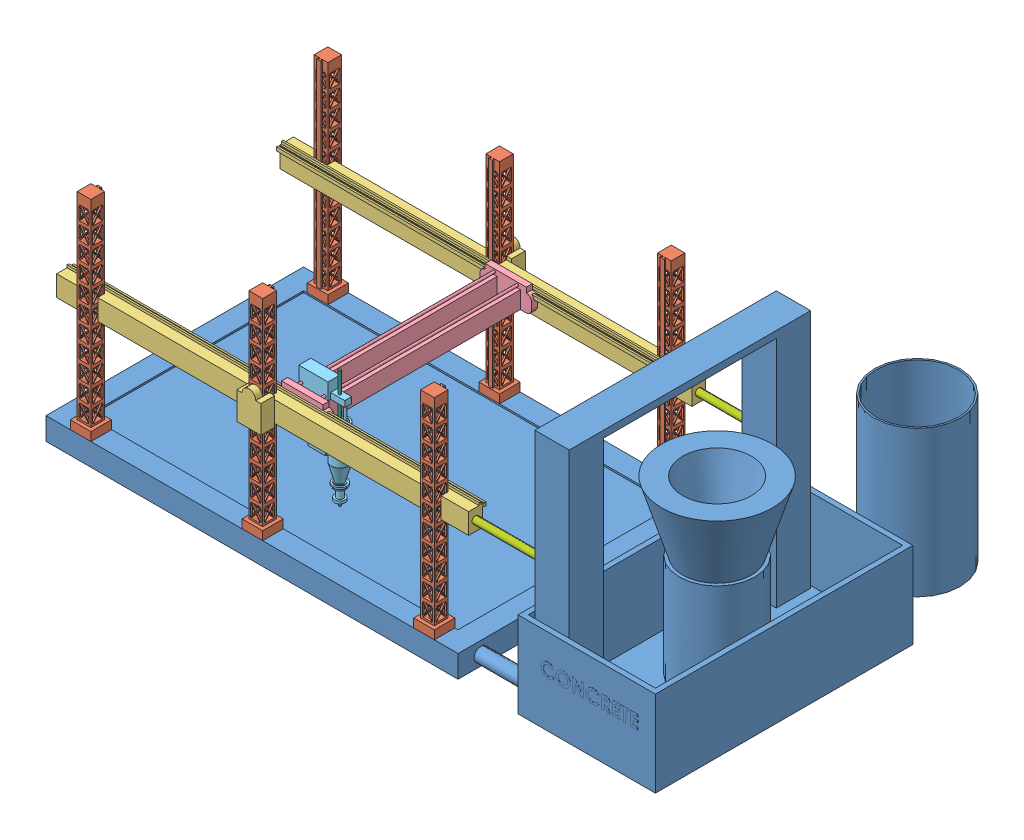
SolidWorks assembly 3-D conc printing, configuration Default. Lengths in mm.
Overall size (9014.85 3683 5637.34).
14 component instances, 7 part files, 41 mates.
Components (placement in the parent):
- base-1: base [Default] at (2368.0723 3073.6153 4815.6142) x (1 0 0) z (0 -1 0) size (9014.85 5587.54 3683)
- coloumn-3: coloumn [Default] at (4912.0124 4600.1553 6466.6142) x (0 -1 0) z (0 0 -1) size (3050.54 304.8 304.8)
- coloumn-4: coloumn [Default] at (2371.8654 4600.1553 3164.6142) x (0 -1 0) z (0 0 1) size (3050.54 304.8 304.8)
- coloumn-5: coloumn [Default] at (4911.8654 4600.1553 3164.6142) x (0 -1 0) z (0 0 1) size (3050.54 304.8 304.8)
- coloumn-6: coloumn [Default] at (-168.1346 4600.1553 3164.6142) x (0 -1 0) z (0 0 1) size (3050.54 304.8 304.8)
- coloumn-2: coloumn [Default] at (-167.9876 4600.1553 6466.6142) x (0 -1 0) z (0 0 -1) size (3050.54 304.8 304.8)
- coloumn-7: coloumn [Default] at (2372.0124 4600.1553 6466.6142) x (0 -1 0) z (0 0 -1) size (3050.54 304.8 304.8)
- beam-1: beam [Default] at (2372.0124 4664.3962 6568.2142) size (6096 508 457.2)
- beam-3: beam [Default] at (2371.8654 4664.3962 3063.0142) x (-1 0 0) z (0 0 -1) size (6096 508 457.2)
- tool post-1: tool post [Default] at (2755.9961 4829.4676 4815.6142) x (0 0 -1) z (0 1 0) size (3098.8 762 330.2)
- nozzle-3: nozzle [Default] at (3059.3592 4054.7676 6112.1341) x (-1 0 0) z (0 -1 0) size (646.26 254 1587.5)
- helix-1: helix [Default] at (3059.3592 4032.5534 6112.1341) x (0.953783 0 -0.300495) z (0 1 0) size (173.07 173.07 1193.48)
- pipe-2: pipe [Default] at (5420.0124 4664.4201 6468.4264) x (0 0 -1) z (1 0 0) size (101.6 101.6 1018.54)
- pipe-3: pipe [Default] at (5419.8654 4650.852 3166.0298) x (0 0 -1) z (1 0 0) size (101.6 101.6 1018.54)
Mates (geometry in assembly coordinates):
- Coincident4: coincident anti-aligned: plane of base-1 through (2368.0723 3073.6153 4815.6142) normal (0 1 0); plane of coloumn-2 through (-167.9876 3073.6153 6466.6142) normal (0 -1 0)
- Coincident7: coincident anti-aligned: plane of base-1 through (2368.0723 3073.6153 4815.6142) normal (0 1 0); plane of coloumn-7 through (2372.0124 3073.6153 6466.6142) normal (0 -1 0)
- Coincident10: coincident anti-aligned: plane of base-1 through (2368.0723 3073.6153 4815.6142) normal (0 1 0); plane of coloumn-3 through (4912.0124 3073.6153 6466.6142) normal (0 -1 0)
- Coincident12: coincident anti-aligned: plane of base-1 through (2368.0723 3073.6153 4815.6142) normal (0 1 0); plane of coloumn-4 through (2371.8654 3073.6153 3164.6142) normal (0 -1 0)
- Coincident13: coincident aligned: plane of base-1 through (-679.9277 2743.4153 2910.6142) normal (0 0 -1); plane of coloumn-4 through (2219.4654 3073.6153 2910.6142) normal (0 0 -1)
- Coincident14: coincident anti-aligned: plane of base-1 through (2368.0723 3073.6153 4815.6142) normal (0 1 0); plane of coloumn-6 through (-168.1346 3073.6153 3164.6142) normal (0 -1 0)
- Coincident15: coincident aligned: plane of base-1 through (-679.9277 2743.4153 2910.6142) normal (0 0 -1); plane of coloumn-6 through (-320.5346 3073.6153 2910.6142) normal (0 0 -1)
- Coincident16: coincident anti-aligned: plane of base-1 through (2368.0723 3073.6153 4815.6142) normal (0 1 0); plane of coloumn-5 through (4911.8654 3073.6153 3164.6142) normal (0 -1 0)
- Coincident17: coincident aligned: plane of base-1 through (-679.9277 2743.4153 2910.6142) normal (0 0 -1); plane of coloumn-5 through (4759.4654 3073.6153 2910.6142) normal (0 0 -1)
- Coincident19: coincident aligned: plane of base-1 through (-679.9277 2743.4153 6720.6142) normal (0 0 1); plane of coloumn-3 through (5064.4124 3073.6153 6720.6142) normal (0 0 1)
- Coincident20: coincident aligned: plane of base-1 through (-679.9277 2743.4153 6720.6142) normal (0 0 1); plane of coloumn-7 through (2524.4124 3073.6153 6720.6142) normal (0 0 1)
- Coincident21: coincident aligned: plane of base-1 through (-679.9277 2743.4153 6720.6142) normal (0 0 1); plane of coloumn-2 through (-15.5876 3073.6153 6720.6142) normal (0 0 1)
- Coincident24: coincident anti-aligned: plane of coloumn-2 through (-136.2376 3129.6201 6434.8642) normal (0 0 -1); plane of beam-1 through (-199.7376 5782.1132 6434.8642) normal (0 0 1)
- Coincident25: coincident anti-aligned: plane of coloumn-2 through (-66.3876 6124.1553 6669.8142) normal (1 0 0); plane of beam-1 through (-66.3876 5782.1132 6568.2142) normal (-1 0 0)
- Coincident26: coincident anti-aligned: plane of coloumn-7 through (2403.7624 3129.6201 6434.8642) normal (0 0 -1); plane of beam-1 through (2340.2624 5782.1132 6434.8642) normal (0 0 1)
- Coincident27: coincident anti-aligned: plane of coloumn-7 through (2270.4124 6124.1553 6669.8142) normal (-1 0 0); plane of beam-1 through (2270.4124 5782.1132 6568.2142) normal (1 0 0)
- Coincident28: coincident anti-aligned: plane of coloumn-3 through (4943.7624 3129.6201 6434.8642) normal (0 0 -1); plane of beam-1 through (4880.2624 5782.1132 6434.8642) normal (0 0 1)
- Coincident29: coincident anti-aligned: plane of coloumn-3 through (4810.4124 6124.1553 6669.8142) normal (-1 0 0); plane of beam-1 through (4810.4124 5782.1132 6568.2142) normal (1 0 0)
- Distance1: distance = 351.6599 mm aligned: plane of coloumn-3 through (5064.4124 3073.6153 6415.8142) normal (1 0 0); plane of base-1 through (5416.0723 2743.4153 2910.6142) normal (1 0 0)
- LimitDistance2: limit distance = 1307.3591 mm aligned: plane of coloumn-7 through (2270.4124 6124.1553 6669.8142) normal (0 1 0); plane of beam-1 through (-675.9876 4816.7962 6365.0142) normal (0 1 0)
- Coincident43: coincident anti-aligned: plane of coloumn-4 through (2340.1154 3129.6201 3196.3642) normal (0 0 1); plane of beam-3 through (2403.6154 5782.1132 3196.3642) normal (0 0 -1)
- Coincident44: coincident anti-aligned: plane of coloumn-4 through (2270.2654 6124.1553 2961.4142) normal (-1 0 0); plane of beam-3 through (2270.2654 5782.1132 3063.0142) normal (1 0 0)
- Coincident45: coincident anti-aligned: plane of coloumn-6 through (-199.8846 3129.6201 3196.3642) normal (0 0 1); plane of beam-3 through (-136.3846 5782.1132 3196.3642) normal (0 0 -1)
- Coincident47: coincident anti-aligned: plane of coloumn-5 through (4880.1154 3129.6201 3196.3642) normal (0 0 1); plane of beam-3 through (4943.6154 5782.1132 3196.3642) normal (0 0 -1)
- Coincident48: coincident anti-aligned: plane of coloumn-5 through (5013.4654 6124.1553 2961.4142) normal (1 0 0); plane of beam-3 through (5013.4654 5782.1132 3063.0142) normal (-1 0 0)
- LimitDistance4: limit distance = 1307.3591 mm aligned: plane of beam-3 through (5419.8654 4816.7962 3266.2142) normal (0 1 0); plane of coloumn-4 through (2473.4654 6124.1553 2961.4142) normal (0 1 0)
- Distance8: distance = 351.8069 mm aligned: plane of coloumn-5 through (5064.2654 3073.6153 3215.4142) normal (1 0 0); plane of base-1 through (5416.0723 2743.4153 2910.6142) normal (1 0 0)
- Coincident51: coincident anti-aligned: plane of beam-1 through (5491.8544 6086.9132 6314.2142) normal (0 0 -1); plane of tool post-1 through (7320.2407 6086.9132 6314.2142) normal (0 0 1)
- Coincident52: coincident anti-aligned: plane of beam-1 through (5491.8544 6036.1132 6339.6142) normal (0 -1 0); plane of tool post-1 through (7320.2407 6036.1132 6339.6142) normal (0 1 0)
- Coincident56: coincident anti-aligned: plane of beam-3 through (-747.9767 6036.1132 3291.6142) normal (0 -1 0); plane of tool post-1 through (7320.2407 6036.1132 3291.6142) normal (0 1 0)
- LimitDistance5: limit distance = 2283.0163 mm aligned: plane of tool post-1 through (3136.9961 4575.4676 6365.0142) normal (1 0 0); plane of beam-1 through (5420.0124 4511.9962 6365.0142) normal (1 0 0)
- Coincident57: coincident anti-aligned: plane of tool post-1 through (3064.7329 5845.5846 6276.1142) normal (-1 0 0); plane of nozzle-3 through (3064.7329 5324.8846 5080.491) normal (1 0 0)
- Parallel1: parallel anti-aligned: plane of tool post-1 through (3064.7329 5845.5846 6276.1142) normal (0 0 -1); plane of nozzle-3 through (2810.7329 5324.8846 5118.589) normal (0 0 1)
- Concentric1: concentric anti-aligned: cylinder of tool post-1 through (3109.1829 6137.6846 3301.2327) axis (0 0 1) radius 19.05; cylinder of nozzle-3 through (3109.1829 6137.6846 5207.491) axis (0 0 -1) radius 19.05
- Concentric4: concentric aligned: cylinder of nozzle-3 through (3241.096 6213.8846 5080.491) axis (0 -1 0) radius 19.05; cylinder of helix-1 through (3241.096 6493.6763 5080.491) axis (0 -1 0) radius 19.05
- LimitDistance6: limit distance = 75.0801 mm anti-aligned: plane of tool post-1 through (2882.9961 4575.4676 6276.1142) normal (0 0 -1); plane of nozzle-3 through (2971.8961 4829.4676 6201.0341) normal (0 0 1)
- Distance12: distance = 660.7917 mm aligned: plane of helix-1 through (3059.3592 5223.5594 6112.1341) normal (0 1 0); plane of nozzle-3 through (3059.3592 4562.7676 6112.1341) normal (0 1 0)
- Coincident60: coincident anti-aligned: plane of beam-1 through (5420.0124 5782.1132 6365.0142) normal (1 0 0); plane of pipe-2 through (5420.0124 5934.5371 6468.4264) normal (-1 0 0)
- Lock3: lock: unknown of beam-1; unknown of pipe-2
- Coincident61: coincident anti-aligned: plane of beam-3 through (5419.8654 5782.1132 3266.2142) normal (1 0 0); plane of pipe-3 through (5419.8654 5920.969 3166.0298) normal (-1 0 0)
- Lock4: lock: unknown of beam-3; unknown of pipe-3
